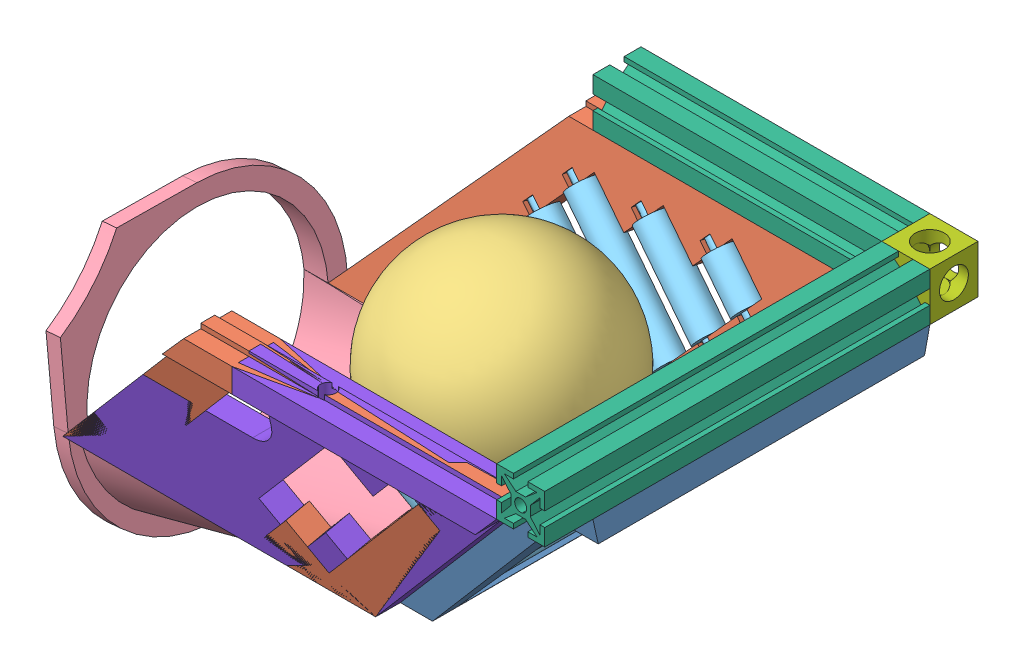
SolidWorks assembly GrabberAssembly, configuration Default. Lengths in mm.
Overall size (131.88 84.83 90).
18 component instances, 8 part files, 29 mates.
Components (placement in the parent):
- GrabberBack-1: GrabberBack [Default] at (1.2203 12.6182 56.7143) size (50 46 70)
- GrabberSide-1: GrabberSide [Default] at (-11.2797 12.6182 31.7143) x (0 0 -1) z (1 0 0) size (90 46 105)
- Ball2018-1: Ball2018 [Default] at (-9.6864 33.8388 49.7914) x (-0.868412 -0.205079 -0.451446) z (0.489843 -0.213608 -0.845237) size (44.5 44.5 44.5)
- GrabberBottom-1: GrabberBottom [Default] at (20.4355 9.6113 56.7143) x (0 0 1) z (-0.965926 -0.258819 0) size (58.17 57.81 90.14)
- GrabberRollingCylinder-1: GrabberRollingCylinder [BackCylinder] at (36.0299 49.5213 56.7143) size (6 6 45)
- GrabberRollingCylinder-2: GrabberRollingCylinder [BackCylinder] at (29.3863 42.0472 56.7143) size (6 6 45)
- GrabberRollingCylinder-3: GrabberRollingCylinder [BackCylinder] at (22.7427 34.5731 56.7143) size (6 6 45)
- GrabberRollingCylinder-4: GrabberRollingCylinder [BackCylinder] at (16.099 27.099 56.7143) size (6 6 45)
- GrabberRollingCylinder-5: GrabberRollingCylinder [BackCylinder] at (9.4554 19.6249 56.7143) size (6 6 45)
- GrabberRollingCylinder-7: GrabberRollingCylinder [Side] at (11.5697 46.2782 22.6977) x (0.144459 0.374112 0.916063) z (0.755295 -0.639779 0.142173) size (6 6 15)
- GrabberRollingCylinder-11: GrabberRollingCylinder [Side] at (11.5697 46.2782 90.7309) x (0.144459 0.374112 -0.916063) z (-0.755295 0.639779 0.142173) size (6 6 15)
- Makerbeam50-1000mm-1: Makerbeam50-1000mm [80mm] at (46.2203 62.6182 21.7143) x (-1 0 0) z (0 0 1) size (10 10 80)
- Makerbeam50-1000mm-2: Makerbeam50-1000mm [60mm] at (41.2203 62.6182 16.7143) x (0 0 -1) z (-1 0 0) size (10 10 60)
- MakerBeam-cube-1: MakerBeam-cube [Default] at (46.2203 57.6182 16.7143) x (1 0 0) z (0 1 0) size (10 10 10)
- GrabberRollingCylinder-18: GrabberRollingCylinder [Side1] at (1.2394 42.104 23.6253) x (0.50054 0.423072 -0.755295) z (0.755295 -0.639779 0.142173) size (6 6 25)
- GrabberRollingCylinder-19: GrabberRollingCylinder [Side2] at (-9.0909 37.9298 24.5529) x (0.50054 0.423072 -0.755295) z (0.755295 -0.639779 0.142173) size (6 6 35)
- GrabberRollingCylinder-20: GrabberRollingCylinder [Side2] at (-15.6448 30.5567 26.1914) x (0.50054 0.423072 -0.755295) z (0.755295 -0.639779 0.142173) size (6 6 35)
- GrabberRight-1: GrabberRight [Left] at (-11.2797 12.6182 31.7143) x (0 0 -1) z (1 0 0) size (20 46 105)
Mates (geometry in assembly coordinates):
- Coincident5: coincident aligned: plane of GrabberBack-1 through (41.2203 57.6182 91.7143) normal (0 1 0); plane of GrabberSide-1 through (41.2203 57.6182 21.7143) normal (0 1 0)
- Coincident6: coincident: point of GrabberBack-1; point of GrabberSide-1
- Coincident7: coincident anti-aligned: line of GrabberBack-1 through (41.2203 57.6182 21.7143) axis (-0.655386 -0.737309 0.163846); line of GrabberSide-1 through (1.2203 12.6182 31.7143) axis (0.655386 0.737309 -0.163846)
- Tangent1: tangent anti-aligned: plane of GrabberBack-1 through (1.2203 12.6182 91.7143) normal (-0.747409 0.664364 0); sphere of Ball2018-1
- Tangent2: tangent anti-aligned: plane of GrabberSide-1 through (41.2203 12.6182 31.7143) normal (0 0.21693 0.976187); sphere of Ball2018-1
- Concentric1: concentric anti-aligned: cylinder of GrabberBack-1 through (36.0299 49.5213 34.2143) axis (0 0 1) radius 1.5; cylinder of GrabberRollingCylinder-1 through (36.0299 49.5213 79.2143) axis (0 0 -1) radius 1.25
- Coincident15: coincident aligned: plane of GrabberBack-1 through (36.0299 49.5213 34.2143) normal (0 0 1); circle of GrabberRollingCylinder-1
- Concentric2: concentric aligned: cylinder of ? through (-35.2462 46.0131 86.7143) axis (0 0 -1) radius 1.5; cylinder of ? through (-35.2462 46.0131 86.7143) axis (0 0 -1) radius 1.25
- Coincident16: coincident anti-aligned: plane of ? through (-35.2462 46.0131 86.7143) normal (0 0 -1); plane of ? through (-35.2462 46.0131 86.7143) normal (0 0 1)
- Coincident18: coincident anti-aligned: plane of GrabberBack-1 through (47.6703 57.6182 91.7143) normal (0 1 0); plane of Makerbeam50-1000mm-1 through (51.2203 57.6182 101.7143) normal (0 -1 0)
- Coincident19: coincident aligned: line of GrabberBack-1 through (51.2203 57.6182 91.7143) axis (0 0 -1); line of Makerbeam50-1000mm-1 through (51.2203 57.6182 101.7143) axis (0 0 -1)
- Coincident20: coincident anti-aligned: plane of GrabberSide-1 through (41.2203 57.6182 21.7143) normal (0 1 0); plane of Makerbeam50-1000mm-2 through (-18.7797 57.6182 21.7143) normal (0 -1 0)
- Coincident21: coincident anti-aligned: line of GrabberSide-1 through (41.2203 57.6182 11.7143) axis (-1 0 0); line of Makerbeam50-1000mm-2 through (-18.7797 57.6182 11.7143) axis (1 0 0)
- Coincident22: coincident: line of GrabberSide-1 through (41.2203 57.6182 11.7143) axis (0 0 1); point of Makerbeam50-1000mm-2
- Coincident23: coincident: line of GrabberBack-1 through (51.2203 57.6182 21.7143) axis (-1 0 0); plane of Makerbeam50-1000mm-1 through (46.2203 62.6182 21.7143) normal (0 0 -1)
- Coincident24: coincident aligned: plane of Makerbeam50-1000mm-1 through (44.7203 67.6182 101.7143) normal (0 1 0); plane of MakerBeam-cube-1 through (46.2203 67.6182 16.7143) normal (0 1 0)
- Coincident25: coincident anti-aligned: plane of Makerbeam50-1000mm-2 through (41.2203 62.6182 16.7143) normal (1 0 0); plane of MakerBeam-cube-1 through (41.2203 67.6182 21.7143) normal (-1 0 0)
- Coincident26: coincident anti-aligned: plane of Makerbeam50-1000mm-1 through (46.2203 62.6182 21.7143) normal (0 0 -1); plane of MakerBeam-cube-1 through (51.2203 67.6182 21.7143) normal (0 0 1)
- Concentric4: concentric aligned: cylinder of GrabberSide-1 through (17.2344 41.4799 23.764) axis (-0.755295 0.639779 -0.142173) radius 1.25; cylinder of GrabberRollingCylinder-7 through (17.2344 41.4799 23.764) axis (-0.755295 0.639779 -0.142173) radius 1.25
- Concentric5: concentric aligned: cylinder of GrabberSide-1 through (10.6806 34.1068 25.4025) axis (-0.755295 0.639779 -0.142173) radius 1.25; cylinder of GrabberRollingCylinder-18 through (10.6806 34.1068 25.4025) axis (-0.755295 0.639779 -0.142173) radius 1.25
- Coincident27: coincident anti-aligned: plane of GrabberSide-1 through (10.6806 34.1068 25.4025) normal (-0.755295 0.639779 -0.142173); circle of GrabberRollingCylinder-18
- Concentric6: concentric aligned: cylinder of GrabberSide-1 through (4.1267 26.7337 27.041) axis (-0.755295 0.639779 -0.142173) radius 1.25; cylinder of GrabberRollingCylinder-19 through (4.1267 26.7337 27.041) axis (-0.755295 0.639779 -0.142173) radius 1.25
- Coincident28: coincident anti-aligned: plane of GrabberSide-1 through (4.1267 26.7337 27.041) normal (-0.755295 0.639779 -0.142173); circle of GrabberRollingCylinder-19
- Coincident29: coincident anti-aligned: plane of GrabberSide-1 through (17.2344 41.4799 23.764) normal (-0.755295 0.639779 -0.142173); plane of GrabberRollingCylinder-7 through (17.2344 41.4799 23.764) normal (0.755295 -0.639779 0.142173)
- Coincident31: coincident: line of GrabberSide-1 through (-63.7797 12.6182 81.7143) axis (0 0 1); plane of GrabberBottom-1 through (-63.8012 12.8636 56.7143) normal (0.996195 0.087156 0)
- Coincident32: coincident: point of GrabberBack-1; point of GrabberRight-1
- Coincident33: coincident aligned: line of Makerbeam50-1000mm-1 through (41.2203 57.6182 101.7143) axis (0 0 -1); line of GrabberRight-1 through (41.2203 57.6182 101.7143) axis (0 0 -1)
- Perpendicular1: perpendicular: line of Makerbeam50-1000mm-1 through (41.2203 61.1182 101.7143) axis (0 -1 0); line of GrabberRight-1 through (41.2203 57.6182 101.7143) axis (-1 0 0)
- Tangent4: tangent: curve of GrabberBottom-1; line of GrabberRight-1 through (1.2203 12.6182 81.7143) axis (-1 0 0)
